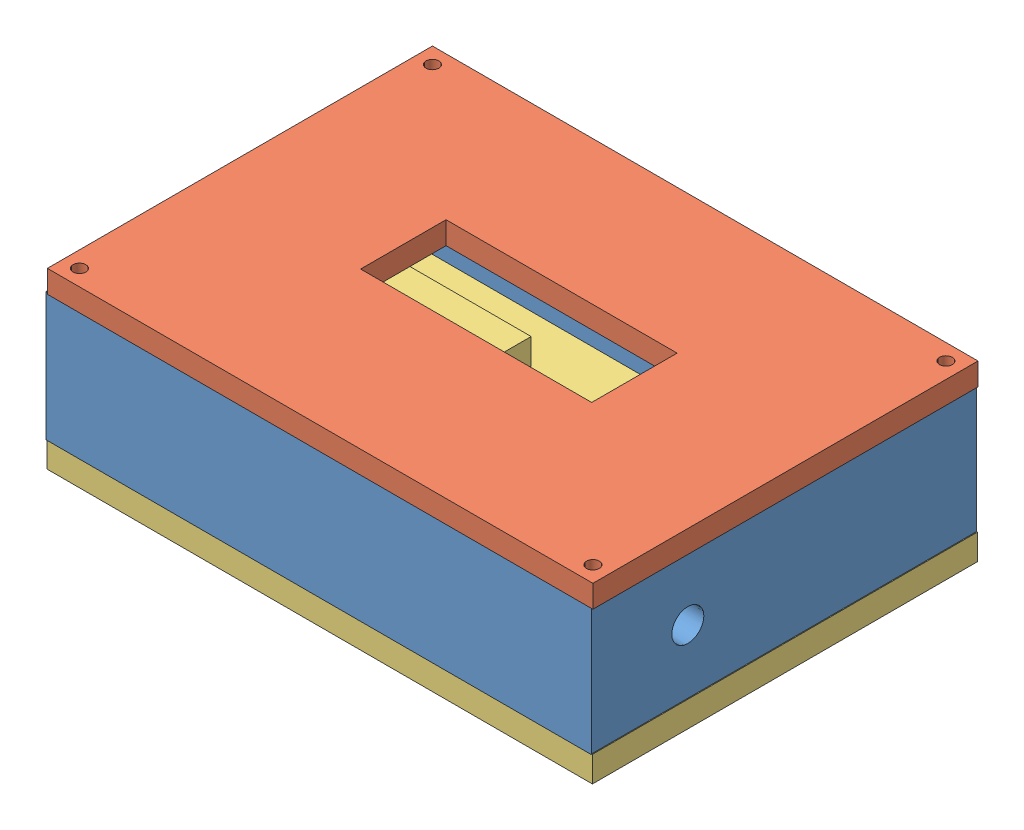
SolidWorks assembly Enclosure_V1, configuration Default. Lengths in mm.
Overall size (170.65 54.47 120.23).
3 component instances, 3 part files, 0 mates.
Components (placement in the parent):
- Part2-1: Part2 [Default] at (83.6498 69.764 132.7091) size (170 40 120)
- Lid-1: Lid [Default] at (84.3044 109.4696 132.936) size (170 7 120)
- Base-1: Base [Default] at (83.9222 62.0009 132.7059) size (170 16 120)
